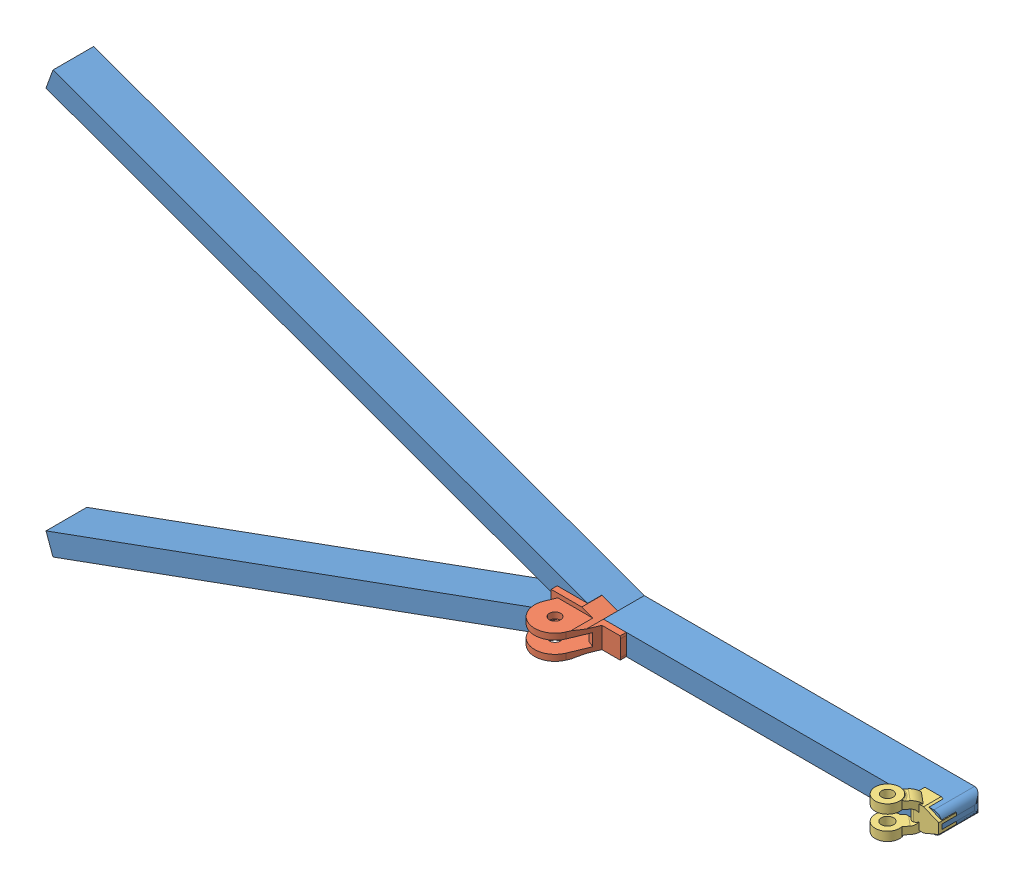
SolidWorks assembly Link_ED_finished, configuration Default. Lengths in mm.
Overall size (221.73 103.39 23.94).
3 component instances, 3 part files, 6 mates.
Components (placement in the parent):
- link_de-1: link_de [Default] at (0.0495 4.3921 85.8042) size (219.62 103.39 10)
- assembly - FORK_cut-1: assembly - FORK_cut [Default] at (-4.351 4.3921 96.9859) x (0.381801 0 -0.924245) z (0.924245 0 0.381801) size (18.09 8 17.62)
- assembly - FORK_cut_front-1: assembly - FORK_cut_front [Default] at (64.1541 4.1955 110.228) x (0.642788 0 -0.766044) z (0.766044 0 0.642788) size (14.74 8.07 8.58)
Mates (geometry in assembly coordinates):
- Parallelo2: parallel aligned: plane of assembly - FORK_cut-1 through (-7.8268 12.3921 92.3042) normal (0 0 -1); plane of assembly - FORK_cut_front-1 through (64.1541 4.1955 92.3042) normal (0 0 -1)
- Simmetrico1: symmetric aligned: plane of assembly - FORK_cut-1 through (3.4928 0.3921 97.3042) normal (0 -1 0); plane of assembly - FORK_cut-1 through (3.4928 8.3921 97.3042) normal (0 1 0)
- Coincidente1: coincident aligned: plane of link_de-1 through (82.792 1.8092 95.8042) normal (1 0 0); plane of assembly - FORK_cut_front-1 through (82.792 3.1421 96.6042) normal (1 0 0)
- Distanza3: distance = 3.5 mm anti-aligned: plane of assembly - FORK_cut_front-1 through (64.1541 4.1955 92.3042) normal (0 0 -1); plane of link_de-1 through (0.0495 4.3921 95.8042) normal (0 0 1)
- Coincidente3: coincident aligned: plane of assembly - FORK_cut-1 through (-7.8268 12.3921 92.3042) normal (0 0 -1); plane of assembly - FORK_cut_front-1 through (64.1541 4.1955 92.3042) normal (0 0 -1)
- Simmetrico2: symmetric aligned: plane of assembly - FORK_cut_front-1 through (79.092 1.5921 96.6042) normal (0 -1 0); plane of assembly - FORK_cut_front-1 through (79.092 7.1921 96.6042) normal (0 1 0)
